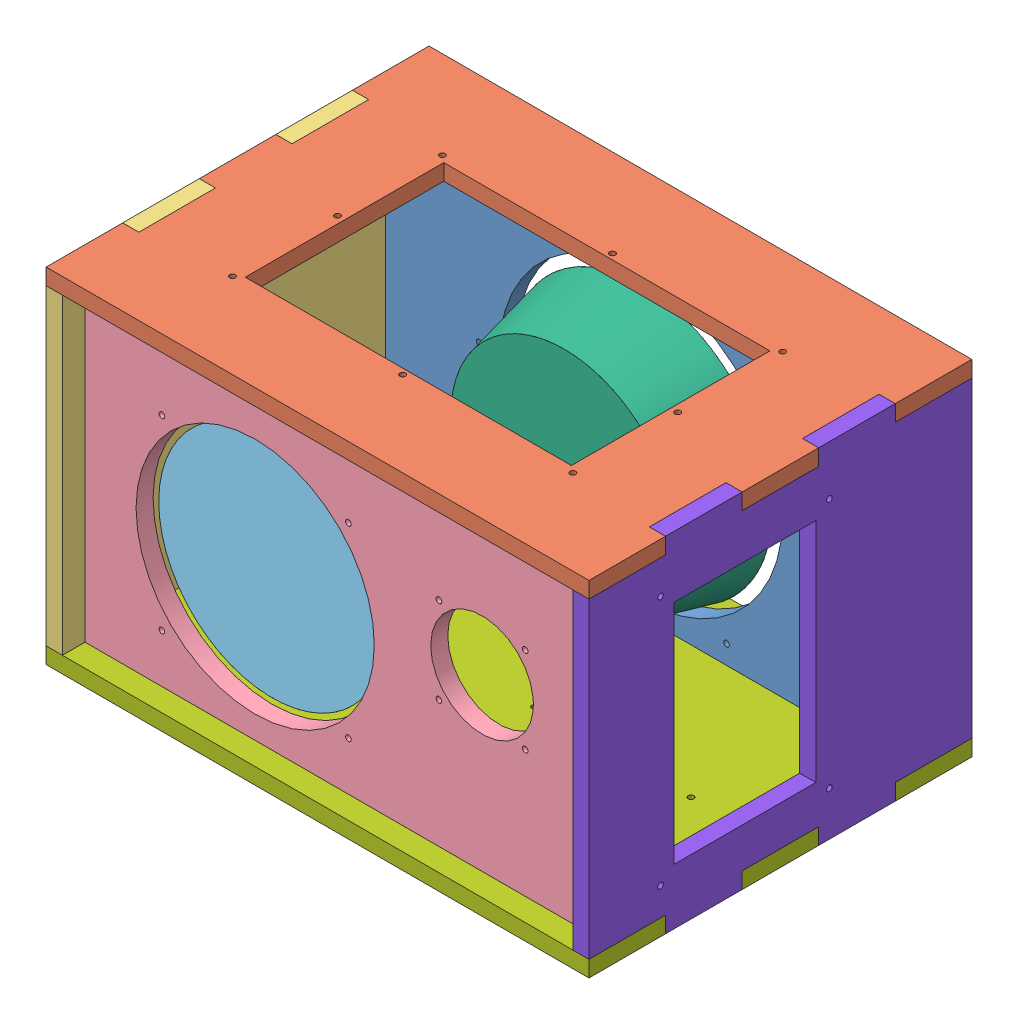
SolidWorks assembly Box Assembly, configuration Default. Lengths in mm.
Overall size (191.4 121.4 135).
10 component instances, 10 part files, 0 mates.
Components (placement in the parent):
- Back Plate-1: Back Plate [Default] at (36.4961 100.143 150.1433) size (180 110 6)
- Top Plate-1: Top Plate [Default] at (36.4961 210.143 256.1433) size (191.4 5.7 135)
- Side Plate-2: Side Plate [Default] at (30.7961 94.143 270.1433) size (5.7 121.4 135)
- Front Plate-1: Front Plate [Default] at (36.4961 100.143 256.1433) size (180 110 6)
- ND91-1: ND91 [Default] at (96.4961 150.143 256.1433) x (-1 0 0) z (0 0 -1) size (80 80 54)
- 830878-1: 830878 [Default] at (126.4961 155.143 156.1433) size (92.5 92.5 27)
- PCB-1: PCB [Default] at (71.4961 200.143 233.1433) (suppressed, hidden)
- Bottom Plate-1: Bottom Plate [Default] at (36.4961 94.443 256.1433) size (191.4 5.7 135)
- Side Plate with Panel-1: Side Plate with Panel [Default] at (216.4961 94.143 270.1433) size (5.7 121.4 135)
- Capacitor Panel-1: Capacitor Panel [Default] at (126.4961 216.143 203.1433) x (1 0 0) z (0 1 0) (suppressed, hidden)
